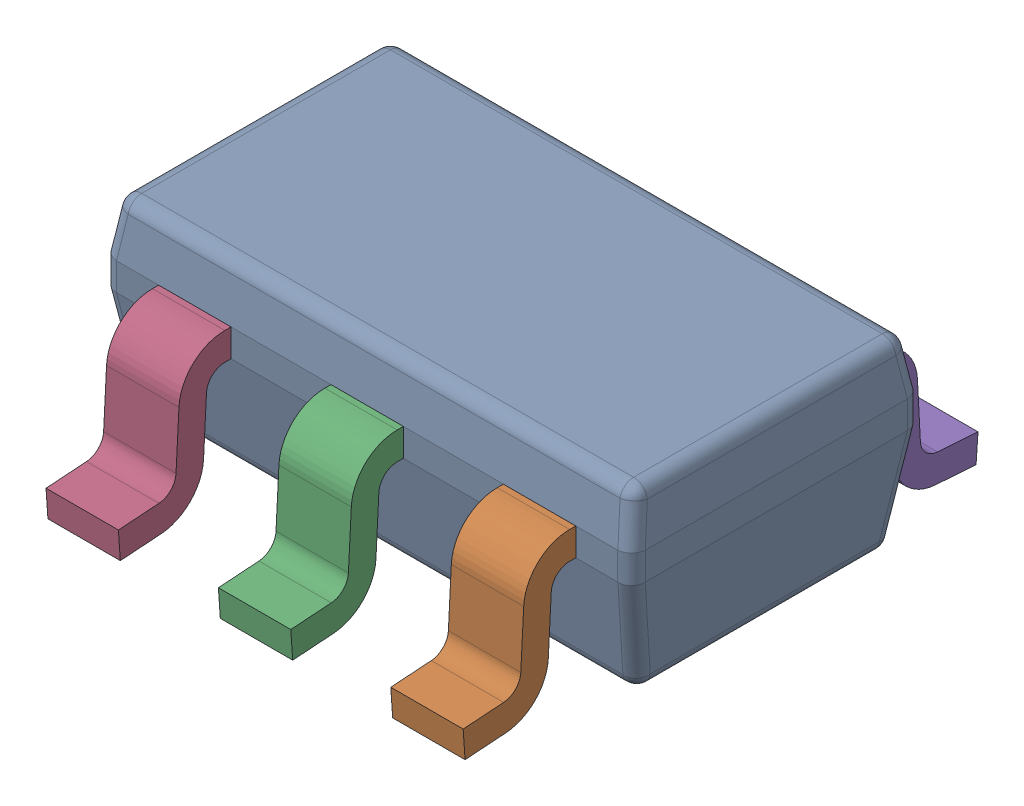
SolidWorks assembly DBV0005AaksMF05A, configuration Default. Lengths in mm.
Overall size (2.93 1.09 2.85).
6 component instances, 2 part files, 0 mates.
Components (placement in the parent):
- BODY_MF05A-1: BODY_MF05A [Default] at origin size (2.93 1.02 1.6)
- LEAD_MF05F-1: LEAD_MF05F [Default] at (0.9525 -0.6096 0.9546) size (0.4 0.81 0.62)
- LEAD_MF05F-2: LEAD_MF05F [Default] at (0 -0.6096 0.9546) size (0.4 0.81 0.62)
- LEAD_MF05F-3: LEAD_MF05F [Default] at (-0.9525 -0.6096 0.9546) size (0.4 0.81 0.62)
- LEAD_MF05F-4: LEAD_MF05F [Default] at (0.9525 -0.6096 -0.9546) x (-1 0 0) z (0 0 -1) size (0.4 0.81 0.62)
- LEAD_MF05F-5: LEAD_MF05F [Default] at (-0.9525 -0.6096 -0.9546) x (-1 0 0) z (0 0 -1) size (0.4 0.81 0.62)
